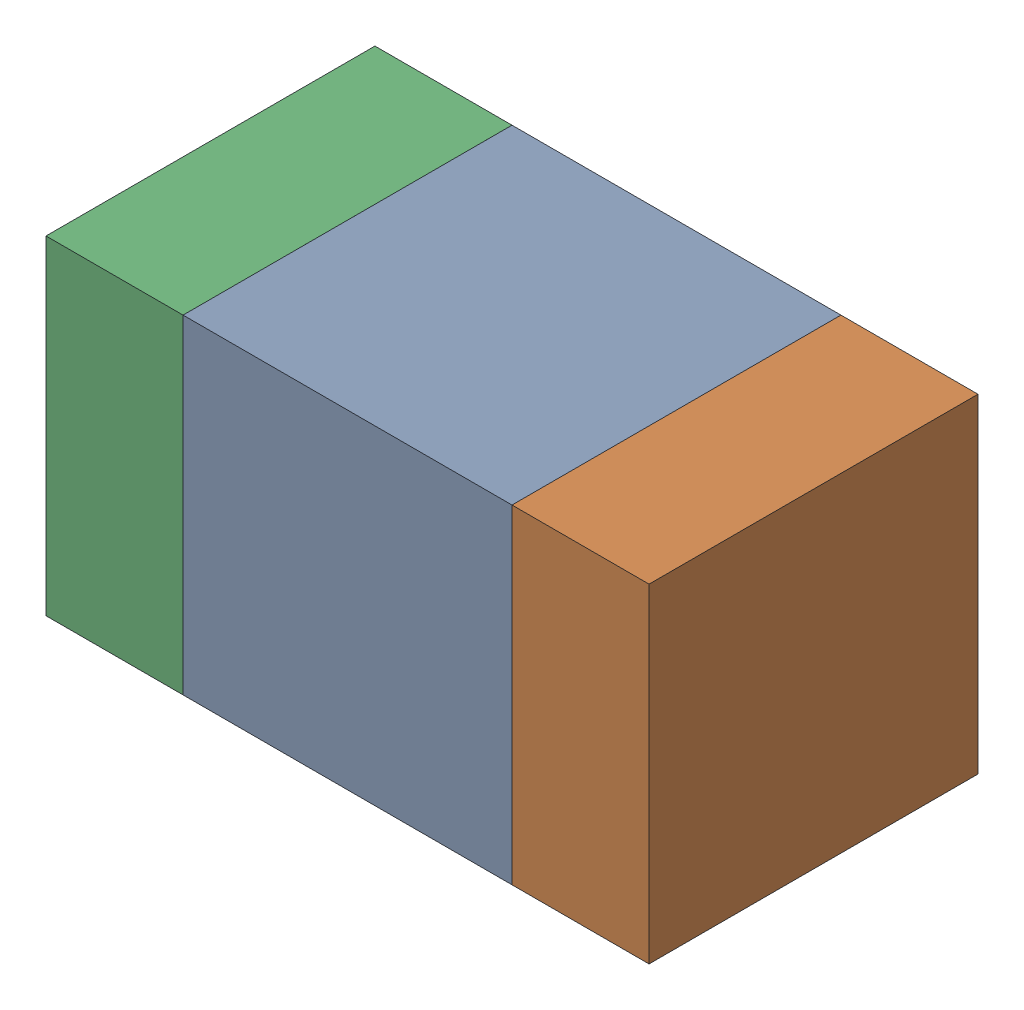
SolidWorks assembly C125_2PCB, configuration Default. Lengths in mm.
Overall size (1.1 0.6 0.6).
6 component instances, 2 part files, 0 mates.
Components (placement in the parent):
- 761606048-1: 761606048 [Default] at (105.8 82.9 0) size (0.6 0.6 0.6)
  - Extruded_9-1: Extruded_9 [Default] at origin size (0.6 0.6 0.6)
- 854785160-1: 854785160 [Default] at (106.225 82.9 0) size (0.25 0.6 0.6)
  - Extruded_19-1: Extruded_19 [Default] at origin size (0.25 0.6 0.6)
- 854785160-2: 854785160 [Default] at (105.375 82.9 0) size (0.25 0.6 0.6)
  - Extruded_19-1: Extruded_19 [Default] at origin size (0.25 0.6 0.6)
